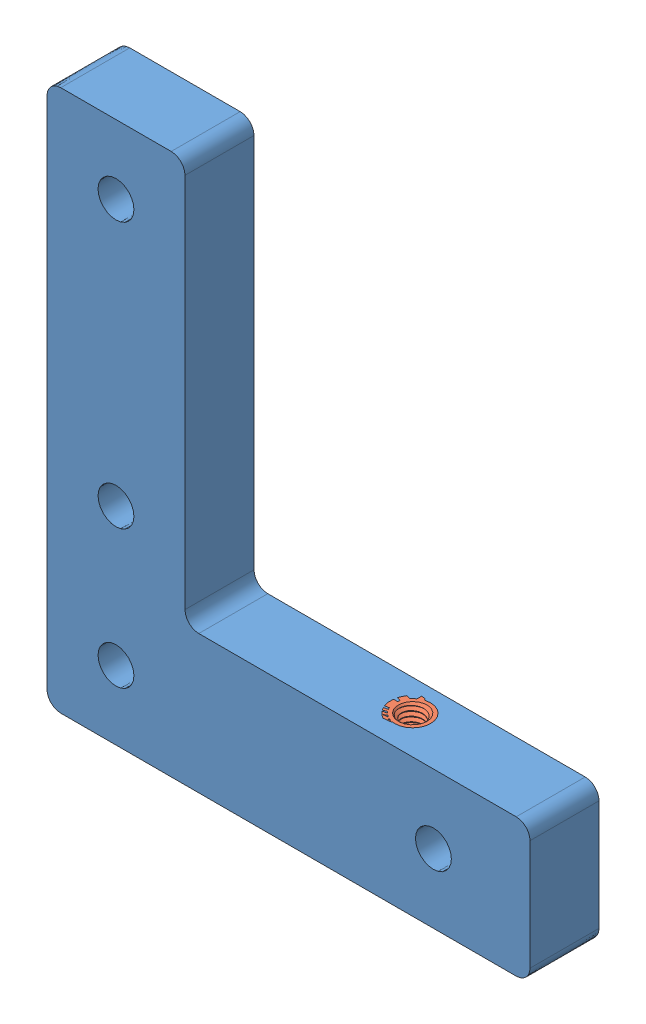
SolidWorks assembly short_motor_corner_plate_spacer_with_insert, configuration Default. Lengths in mm.
Overall size (85 78.5 13).
2 component instances, 2 part files, 3 mates.
Components (placement in the parent):
- motor_corner_bracket_spacer-1: motor_corner_bracket_spacer [Left Motor Corner Bracket Spacer] at (-74.7769 0 0) x (0 1 0) z (-1 0 0) size (78.5 13 85)
- m4_heat_set_insert_long_94180A353-1: m4_heat_set_insert_long_94180A353 [94180A353] at (-27.2769 20 -5.5) x (0.97178 0 0.235889) z (-0.235889 0 0.97178) size (6.35 8.38 6.35)
Mates (geometry in assembly coordinates):
- Coincident1594070439: coincident aligned: plane of motor_corner_bracket_spacer-1 through (-54.7769 20 -10) normal (0 1 0); plane of m4_heat_set_insert_long_94180A353-1 through (-27.2769 20 -5.5) normal (0 1 0)
- Concentric754009867: concentric anti-aligned: cylinder of motor_corner_bracket_spacer-1 through (-27.2769 78.5 -5.5) axis (0 -1 0) radius 2.6; circle of m4_heat_set_insert_long_94180A353-1
- Coincident1594070441: coincident anti-aligned: plane of motor_corner_bracket_spacer-1 through (-4.7769 0 -10) normal (0 -1 0)
